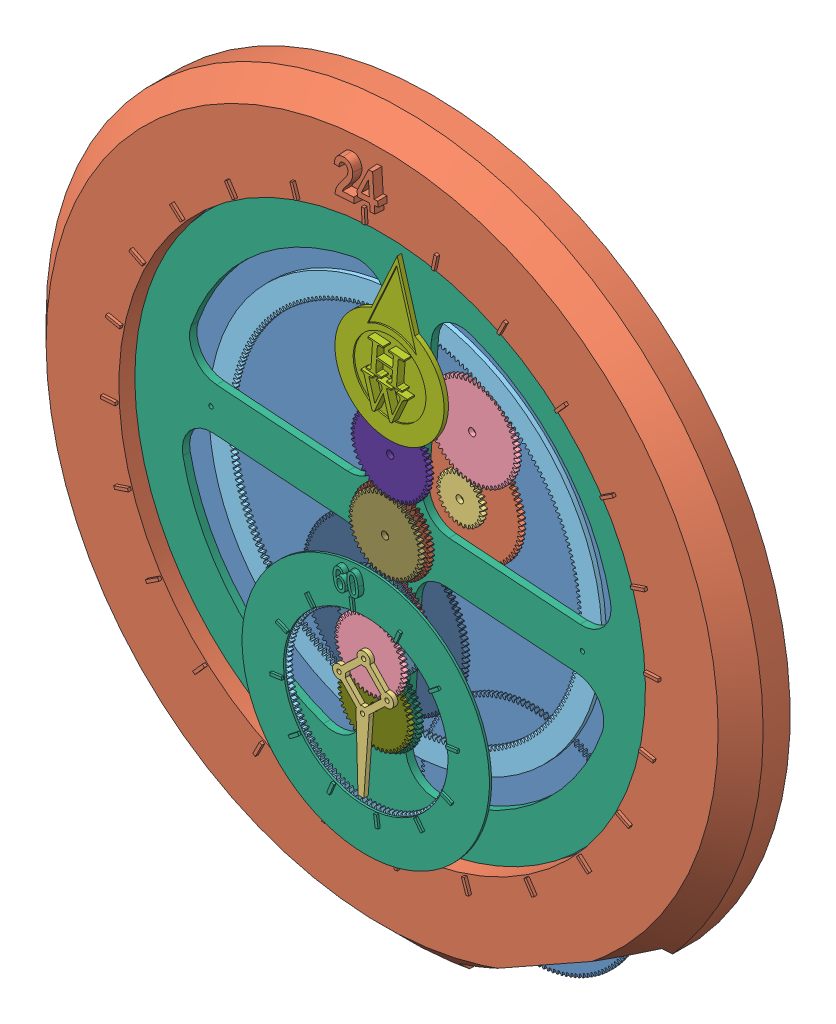
SolidWorks assembly Assem_SKLOP_02_KONACNI, configuration Default. Lengths in mm.
Overall size (664.83 659.75 45.3).
26 component instances, 25 part files, 67 mates.
Components (placement in the parent):
- Podloga-1: Podloga [Default] at (-25.2246 5.9427 4.2733) size (400 400 10)
- Z3'-1: Z3' [DIN - Spur gear 1M 75T 20PA 3FW ---S75A75H50L5.0N] at (12.1154 39.1927 15.2733) x (0 0 1) z (-0.721849 -0.692051 0) size (3 76.98 76.99)
- Z3-1: Z3 [DIN - Spur gear 1M 30T 20PA 3FW ---S30A75H50L5.0N] at (12.1154 39.1927 19.2733) x (0 0 1) z (-0.776322 -0.630336 0) size (3 31.88 32)
- Z2-1: Z2 [DIN - Spur gear 1M 60T 20PA 3FW ---S60A75H50L5.0N] at (20.6354 83.3827 19.2733) x (0 0 1) z (0.628115 0.778121 0) size (3 61.95 61.95)
- Assem_Z1-1: Assem_Z1 [Default] at (-22.0487 40.1725 86.8715) x (0 0 1) z (-0.070602 -0.997505 0) size (9 360 360)
  - Z1-1: Z1 [DIN - Internal spur gear 1M 240T 20PA 3FW ---S240S270OD 1.0AF] at (-67.5981 0.7513 34.3687) size (3 270 270)
  - Centralno kolo-1: Centralno kolo [Default] at (-58.5981 0.7513 34.3687) x (0 1 0) z (-1 0 0) size (360 360 5)
- Z2'-1: Z2' [DIN - Spur gear 1M 36T 20PA 3FW ---S36A75H50L5.0N] at (20.6354 83.3827 0.2733) x (0 0 1) z (0.292027 -0.95641 0) size (3 37.9 37.9)
- Z4'''-1: Z4''' [DIN - Spur gear 1M 144T 20PA 3FW ---S144A75H50L5.0N] at (-25.2246 5.9427 3.2733) x (0 0 -1) z (0.691882 0.722011 0) size (3 145.98 145.98)
- Z4''-1: Z4'' [DIN - Spur gear 1M 25T 20PA 3FW ---S25A75H50L5.0N] at (-25.2246 5.9427 18.2733) x (0 0 -1) z (0.924184 -0.381948 0) size (3 26.93 26.98)
- Z11-1: Z11 [DIN - Spur gear 1M 110T 20PA 3FW ---S110A75H50L5.0N] at (-43.9346 -58.9173 15.2733) x (0 0 1) z (-0.28287 0.959158 0) size (3 111.97 112)
- Z4'-1: Z4' [DIN - Spur gear 1M 52T 20PA 3FW ---S52A75H50L5.0N] at (-25.2246 5.9427 29.2733) x (0 0 1) z (-0.973316 -0.229468 0) size (3 53.94 53.94)
- Z4-1: Z4 [DIN - Spur gear 1M 48T 20PA 3FW ---S48A75H50L5.0N] at (-25.2246 5.9427 36.2733) x (0 0 -1) z (-0.396657 -0.917967 0) size (3 49.93 49.93)
- Z5'-1: Z5' [DIN - Spur gear 1M 54T 20PA 3FW ---S54A75H50L5.0N] at (-28.9665 -46.9251 29.2733) x (0 0 1) z (0.434424 0.900708 0) size (3 55.94 56)
- Z5-1: Z5 [DIN - Spur gear 1M 58T 20PA 3FW ---S58A75H50L5.0N] at (-28.9665 -46.9251 33.2733) x (0 0 1) z (-0.989543 0.144236 0) size (3 59.94 60)
- Z6'-1: Z6' [DIN - Spur gear 1M 52T 20PA 3FW ---S52A75H50L5.0N] at (-32.7085 -99.7928 32.2733) x (0 0 -1) z (-0.817955 0.575283 0) size (3 53.94 53.94)
- Z6-1: Z6 [DIN - Spur gear 1M 48T 20PA 3FW ---S48A75H50L5.0N] at (-32.7085 -99.7928 36.2733) x (0 0 -1) z (0.487482 -0.873133 0) size (3 49.93 49.93)
- Z7-1: Z7 [DIN - Spur gear 1M 52T 20PA 3FW ---S52A75H50L5.0N] at (-21.6945 55.8179 36.2733) x (0 0 -1) z (0.379041 0.92538 0) size (3 53.94 53.94)
- Z8-1: Z8 [DIN - Spur gear 1M 48T 20PA 3FW ---S48A75H50L5.0N] at (-18.1644 105.6931 36.2733) x (0 0 -1) z (-0.619697 -0.784841 0) size (3 49.93 49.93)
- Z12'-1: Z12' [DIN - Spur gear 1M 150T 20PA 3FW ---S150A75H50L5.0N] at (57.5954 -140.1073 15.2733) x (0 0 1) z (-0.538075 0.842897 0) size (3 151.98 152)
- Poklopac-1: Poklopac [Default] at (-25.2246 5.9427 14.2733) x (0.490689 -0.871335 0) z (-0.871335 -0.490689 0) size (479.58 40 492.93)
- Kazaljka-1: Kazaljka [Default] at (-31.9633 -66.8012 41.2733) x (-0.999745 0.02258 0) z (0.02258 0.999745 0) size (42 3 87.5)
- Z9-1: Z9 [DIN - Spur gear 1M 46T 20PA 3FW ---S46A75H50L5.0N] at (-31.9633 -66.8012 37.2733) x (0 0 1) z (-0.277017 -0.960865 0) size (3 47.93 48)
- Z10-1: Z10 [DIN - Internal spur gear 1M 112T 20PA 3FW ---S112S150OD 1.0AF] at (-32.7085 -99.7928 37.2733) x (0 0 1) z (-0.999992 -0.004112 0) size (3 150 150)
- Minutaljka_02-1: Minutaljka_02 [Default] at (-32.7085 -99.7928 40.5733) x (0.926741 -0.3757 0) z (0 0 1) size (170 170 5)
- HW kazaljka-1: HW kazaljka [Default] at (-18.1644 105.6931 37.2733) x (0.997505 -0.070602 0) z (0 0 1) size (75 112.5 7)
Mates (geometry in assembly coordinates):
- Coincident1: coincident aligned: axis of Z3'-1 through (12.1154 39.1927 18.2733) axis (0 0 -1); axis of Z3-1 through (12.1154 39.1927 22.2733) axis (0 0 -1)
- Distance1: distance = 1 mm anti-aligned: plane of Z3-1 through (12.1154 39.1927 19.2733) normal (0 0 -1); plane of Z3'-1 through (12.1154 39.1927 18.2733) normal (0 0 1)
- Coincident3: coincident anti-aligned: axis of Podloga-1 through (12.1154 39.1927 4.2733) axis (0 0 1); axis of Z3'-1 through (12.1154 39.1927 18.2733) axis (0 0 -1)
- Distance2: distance = 1 mm anti-aligned: plane of Z3'-1 through (12.1154 39.1927 15.2733) normal (0 0 -1); plane of Podloga-1 through (-25.2246 5.9427 14.2733) normal (0 0 1)
- GearMate1: gear = 1 : 1 mm: axis of Z3-1 through (12.1154 39.1927 22.2733) axis (0 0 -1); axis of Z3'-1 through (12.1154 39.1927 18.2733) axis (0 0 -1)
- Coincident5: coincident anti-aligned: axis of Podloga-1 through (20.6354 83.3827 4.2733) axis (0 0 1); axis of Z2-1 through (20.6354 83.3827 22.2733) axis (0 0 -1)
- Coincident6: coincident aligned: plane of Z3-1 through (12.1154 39.1927 22.2733) normal (0 0 1); plane of Z2-1 through (20.6354 83.3827 22.2733) normal (0 0 1)
- GearMate2: gear = 30 : 60 mm: axis of Z2-1 through (20.6354 83.3827 22.2733) axis (0 0 -1); axis of Z3-1 through (12.1154 39.1927 22.2733) axis (0 0 -1)
- Coincident8: coincident anti-aligned: axis of Podloga-1 through (-25.2246 5.9427 14.2733) axis (0 0 -1); axis of Assem_Z1-1/Centralno kolo-1 through (-25.2246 5.9427 23.2733) axis (0 0 1)
- Coincident10: coincident anti-aligned: axis of Podloga-1 through (20.6354 83.3827 4.2733) axis (0 0 1); axis of Z2'-1 through (20.6354 83.3827 3.2733) axis (0 0 -1)
- Distance3: distance = 1 mm anti-aligned: plane of Z2'-1 through (20.6354 83.3827 3.2733) normal (0 0 1); plane of Podloga-1 through (-25.2246 5.9427 4.2733) normal (0 0 -1)
- GearMate4: gear = 1 : 1 mm: axis of Z2'-1 through (20.6354 83.3827 3.2733) axis (0 0 -1); axis of Z2-1 through (20.6354 83.3827 22.2733) axis (0 0 -1)
- Coincident12: coincident aligned: plane of Z2-1 through (20.6354 83.3827 22.2733) normal (0 0 1); plane of Assem_Z1-1/Z1-1 through (-16.823 124.6457 22.2733) normal (0 0 1)
- GearMate6: gear = 240 : 60 mm: axis of Z2-1 through (20.6354 83.3827 22.2733) axis (0 0 -1); axis of Assem_Z1-1/Z1-1 through (-25.2246 5.9427 22.2733) axis (0 0 -1)
- Coincident13: coincident anti-aligned: axis of Podloga-1 through (-25.2246 5.9427 14.2733) axis (0 0 -1); axis of Z4'''-1 through (-25.2246 5.9427 0.2733) axis (0 0 1)
- Coincident14: coincident aligned: plane of Z2'-1 through (20.6354 83.3827 0.2733) normal (0 0 -1); plane of Z4'''-1 through (-25.2246 5.9427 0.2733) normal (0 0 -1)
- GearMate7: gear = 144 : 36 mm: axis of Z2'-1 through (20.6354 83.3827 3.2733) axis (0 0 -1); axis of Z4'''-1 through (-25.2246 5.9427 0.2733) axis (0 0 1)
- Coincident15: coincident anti-aligned: axis of Podloga-1 through (-25.2246 5.9427 14.2733) axis (0 0 -1); axis of Z4''-1 through (-25.2246 5.9427 15.2733) axis (0 0 1)
- Coincident16: coincident aligned: plane of Z3'-1 through (12.1154 39.1927 18.2733) normal (0 0 1); plane of Z4''-1 through (-25.2246 5.9427 18.2733) normal (0 0 1)
- GearMate8: gear = 75 : 25 mm: axis of Z4''-1 through (-25.2246 5.9427 15.2733) axis (0 0 1); axis of Z3'-1 through (12.1154 39.1927 18.2733) axis (0 0 -1)
- Coincident17: coincident anti-aligned: axis of Podloga-1 through (-43.9346 -58.9173 4.2733) axis (0 0 1); axis of Z11-1 through (-43.9346 -58.9173 18.2733) axis (0 0 -1)
- Coincident18: coincident aligned: plane of Z4''-1 through (-25.2246 5.9427 18.2733) normal (0 0 1); plane of Z11-1 through (-43.9346 -58.9173 18.2733) normal (0 0 1)
- GearMate9: gear = 110 : 25 mm: axis of Z4''-1 through (-25.2246 5.9427 15.2733) axis (0 0 1); axis of Z11-1 through (-43.9346 -58.9173 18.2733) axis (0 0 -1)
- Coincident21: coincident anti-aligned: axis of Z4'-1 through (-25.2246 5.9427 32.2733) axis (0 0 -1); axis of Z4-1 through (-25.2246 5.9427 33.2733) axis (0 0 1)
- Coincident22: coincident anti-aligned: axis of Assem_Z1-1/Centralno kolo-1 through (-25.2246 5.9427 23.2733) axis (0 0 1); axis of Z4'-1 through (-25.2246 5.9427 32.2733) axis (0 0 -1)
- Distance4: distance = 1 mm anti-aligned: plane of Z4-1 through (-25.2246 5.9427 33.2733) normal (0 0 -1); plane of Z4'-1 through (-25.2246 5.9427 32.2733) normal (0 0 1)
- Distance5: distance = 1 mm anti-aligned: plane of Z4'-1 through (-25.2246 5.9427 29.2733) normal (0 0 -1); plane of Assem_Z1-1/Centralno kolo-1 through (-25.2246 5.9427 28.2733) normal (0 0 1)
- GearMate11: gear = 1 : 1 mm: axis of Z4'''-1 through (-25.2246 5.9427 0.2733) axis (0 0 1); axis of Z4-1 through (-25.2246 5.9427 33.2733) axis (0 0 1)
- GearMate12: gear = 1 : 1 mm: axis of Z4''-1 through (-25.2246 5.9427 15.2733) axis (0 0 1); axis of Z4'-1 through (-25.2246 5.9427 32.2733) axis (0 0 -1)
- Coincident25: coincident aligned: axis of Z5'-1 through (-28.9665 -46.9251 32.2733) axis (0 0 -1); axis of Z5-1 through (-28.9665 -46.9251 36.2733) axis (0 0 -1)
- Coincident26: coincident aligned: axis of Assem_Z1-1/Centralno kolo-1 through (-28.9665 -46.9251 28.2733) axis (0 0 -1); axis of Z5'-1 through (-28.9665 -46.9251 32.2733) axis (0 0 -1)
- Coincident27: coincident aligned: plane of Z4'-1 through (-25.2246 5.9427 32.2733) normal (0 0 1); plane of Z5'-1 through (-28.9665 -46.9251 32.2733) normal (0 0 1)
- GearMate13: gear = 54 : 52 mm: axis of Z4'-1 through (-25.2246 5.9427 32.2733) axis (0 0 -1); axis of Z5'-1 through (-28.9665 -46.9251 32.2733) axis (0 0 -1)
- Coincident28: coincident aligned: plane of Z4-1 through (-25.2246 5.9427 36.2733) normal (0 0 1); plane of Z5-1 through (-28.9665 -46.9251 36.2733) normal (0 0 1)
- GearMate14: gear = 58 : 48 mm: axis of Z4-1 through (-25.2246 5.9427 33.2733) axis (0 0 1); axis of Z5-1 through (-28.9665 -46.9251 36.2733) axis (0 0 -1)
- Coincident29: coincident aligned: axis of Z6'-1 through (-32.7085 -99.7928 29.2733) axis (0 0 1); axis of Z6-1 through (-32.7085 -99.7928 33.2733) axis (0 0 1)
- Coincident30: coincident anti-aligned: axis of Assem_Z1-1/Centralno kolo-1 through (-32.7085 -99.7928 28.2733) axis (0 0 -1); axis of Z6'-1 through (-32.7085 -99.7928 29.2733) axis (0 0 1)
- Coincident31: coincident aligned: plane of Z5'-1 through (-28.9665 -46.9251 32.2733) normal (0 0 1); plane of Z6'-1 through (-32.7085 -99.7928 32.2733) normal (0 0 1)
- GearMate15: gear = 52 : 54 mm: axis of Z5'-1 through (-28.9665 -46.9251 32.2733) axis (0 0 -1); axis of Z6'-1 through (-32.7085 -99.7928 29.2733) axis (0 0 1)
- Coincident32: coincident aligned: plane of Z5-1 through (-28.9665 -46.9251 36.2733) normal (0 0 1); plane of Z6-1 through (-32.7085 -99.7928 36.2733) normal (0 0 1)
- GearMate16: gear = 58 : 48 mm: axis of Z6-1 through (-32.7085 -99.7928 33.2733) axis (0 0 1); axis of Z5-1 through (-28.9665 -46.9251 36.2733) axis (0 0 -1)
- Coincident33: coincident anti-aligned: axis of Assem_Z1-1/Centralno kolo-1 through (-21.6945 55.8179 28.2733) axis (0 0 -1); axis of Z7-1 through (-21.6945 55.8179 33.2733) axis (0 0 1)
- Coincident34: coincident anti-aligned: axis of Assem_Z1-1/Centralno kolo-1 through (-18.1644 105.6931 28.2733) axis (0 0 -1); axis of Z8-1 through (-18.1644 105.6931 33.2733) axis (0 0 1)
- Coincident35: coincident aligned: plane of Z4-1 through (-25.2246 5.9427 36.2733) normal (0 0 1); plane of Z7-1 through (-21.6945 55.8179 36.2733) normal (0 0 1)
- GearMate17: gear = 52 : 48 mm: axis of Z4-1 through (-25.2246 5.9427 33.2733) axis (0 0 1); axis of Z7-1 through (-21.6945 55.8179 33.2733) axis (0 0 1)
- Coincident36: coincident aligned: plane of Z7-1 through (-21.6945 55.8179 36.2733) normal (0 0 1); plane of Z8-1 through (-18.1644 105.6931 36.2733) normal (0 0 1)
- GearMate18: gear = 48 : 52 mm: axis of Z7-1 through (-21.6945 55.8179 33.2733) axis (0 0 1); axis of Z8-1 through (-18.1644 105.6931 33.2733) axis (0 0 1)
- Coincident37: coincident anti-aligned: axis of Podloga-1 through (57.5954 -140.1073 4.2733) axis (0 0 1); axis of Z12'-1 through (57.5954 -140.1073 18.2733) axis (0 0 -1)
- Coincident38: coincident aligned: plane of Z11-1 through (-43.9346 -58.9173 18.2733) normal (0 0 1); plane of Z12'-1 through (57.5954 -140.1073 18.2733) normal (0 0 1)
- GearMate19: gear = 150 : 110 mm: axis of Z11-1 through (-43.9346 -58.9173 18.2733) axis (0 0 -1); axis of Z12'-1 through (57.5954 -140.1073 18.2733) axis (0 0 -1)
- Concentric1: concentric aligned: cylinder of Podloga-1 through (-25.2246 5.9427 14.2733) axis (0 0 -1) radius 200; cylinder of Poklopac-1 through (-25.2246 5.9427 14.2733) axis (0 0 -1) radius 199.0054
- Coincident39: coincident anti-aligned: plane of Podloga-1 through (-25.2246 5.9427 14.2733) normal (0 0 1); plane of Poklopac-1 through (69.969 -163.0963 14.2733) normal (0 0 -1)
- Lock1: lock: unknown of Podloga-1; unknown of Poklopac-1
- Coincident40: coincident anti-aligned: axis of Z6'-1 through (-32.7085 -99.7928 29.2733) axis (0 0 1); axis of Kazaljka-1 through (-32.7085 -99.7928 44.2733) axis (0 0 -1)
- Distance6: distance = 5 mm anti-aligned: plane of Kazaljka-1 through (-32.7085 -99.7928 41.2733) normal (0 0 -1); plane of Z6-1 through (-32.7085 -99.7928 36.2733) normal (0 0 1)
- GearMate20: gear = 1 : 1 mm: axis of Z6'-1 through (-32.7085 -99.7928 29.2733) axis (0 0 1); axis of Kazaljka-1 through (-32.7085 -99.7928 44.2733) axis (0 0 -1)
- Coincident42: coincident aligned: axis of Kazaljka-1 through (-31.9633 -66.8012 44.2733) axis (0 0 -1); axis of Z9-1 through (-31.9633 -66.8012 40.2733) axis (0 0 -1)
- Distance7: distance = 1 mm anti-aligned: plane of Kazaljka-1 through (-32.7085 -99.7928 41.2733) normal (0 0 -1); plane of Z9-1 through (-31.9633 -66.8012 40.2733) normal (0 0 1)
- Coincident44: coincident aligned: axis of Kazaljka-1 through (-32.7085 -99.7928 44.2733) axis (0 0 -1); axis of Z10-1 through (-32.7085 -99.7928 40.2733) axis (0 0 -1)
- Coincident45: coincident aligned: plane of Z9-1 through (-31.9633 -66.8012 40.2733) normal (0 0 1); plane of Z10-1 through (22.2911 -99.5667 40.2733) normal (0 0 1)
- GearMate21: gear = 1 : 1 mm: axis of Z10-1 through (-32.7085 -99.7928 40.2733) axis (0 0 -1); axis of Z6-1 through (-32.7085 -99.7928 33.2733) axis (0 0 1)
- GearMate22: gear = 112 : 46 mm: axis of Z9-1 through (-31.9633 -66.8012 40.2733) axis (0 0 -1); axis of Z10-1 through (-32.7085 -99.7928 40.2733) axis (0 0 -1)
- Coincident46: coincident aligned: axis of Kazaljka-1 through (-32.7085 -99.7928 44.2733) axis (0 0 -1); axis of Minutaljka_02-1 through (-32.7085 -99.7928 42.0733) axis (0 0 -1)
- Distance8: distance = 0.3 mm anti-aligned: plane of Minutaljka_02-1 through (-32.7085 -99.7928 40.5733) normal (0 0 -1); plane of Z10-1 through (22.2911 -99.5667 40.2733) normal (0 0 1)
- Coincident47: coincident anti-aligned: axis of Z8-1 through (-18.1644 105.6931 33.2733) axis (0 0 1); axis of HW kazaljka-1 through (-18.1644 105.6931 40.2733) axis (0 0 -1)
- Distance9: distance = 1 mm anti-aligned: plane of HW kazaljka-1 through (-18.1644 105.6931 37.2733) normal (0 0 -1); plane of Z8-1 through (-18.1644 105.6931 36.2733) normal (0 0 1)
- Coincident48: coincident anti-aligned: plane of Assem_Z1-1/Centralno kolo-1; plane of HW kazaljka-1
